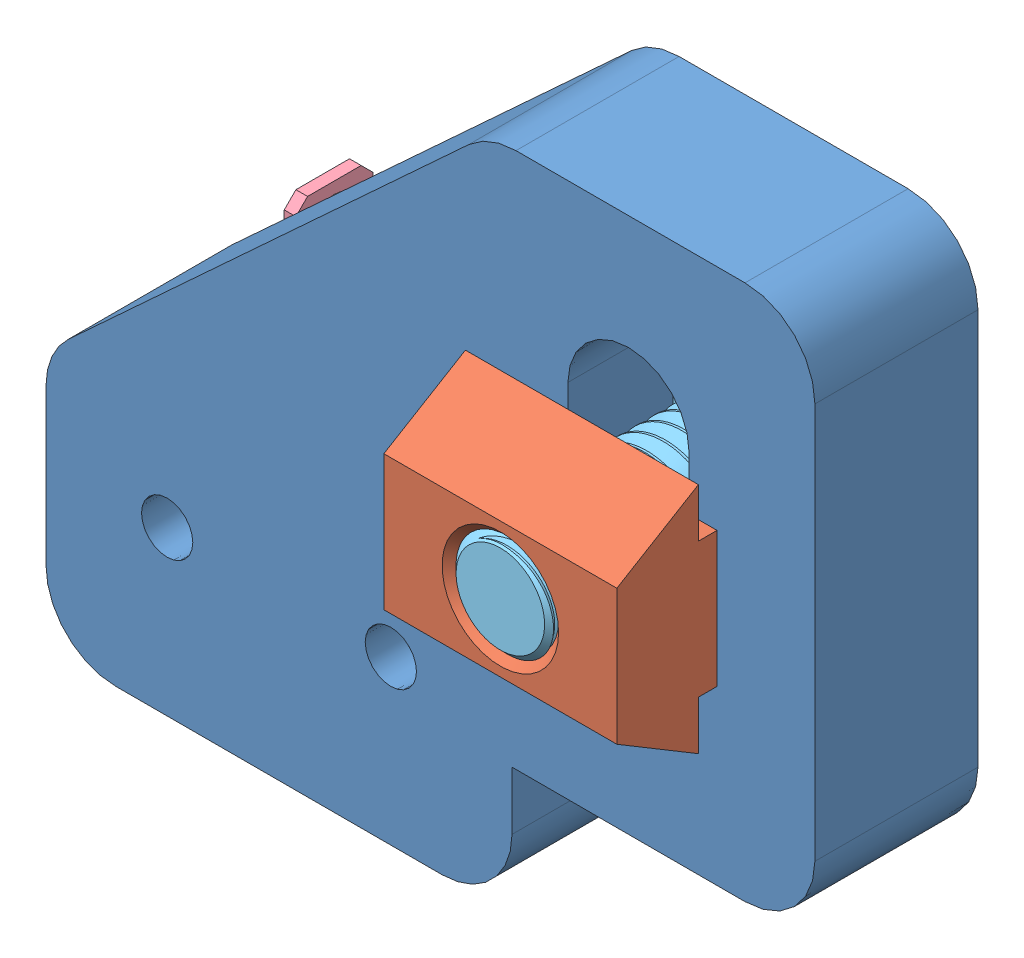
SolidWorks assembly Z Endstop, configuration Default. Lengths in mm.
Overall size (33 31.91 21.1).
6 component instances, 5 part files, 12 mates.
Components (placement in the parent):
- Z Endstop Mount V2-1: Z Endstop Mount V2 [Default] at origin size (33 28.5 7)
- HNTTSN5-5-1: HNTTSN5-5 [Default] at (25 17 8.2) x (0 0 -1) z (1 0 0) size (4.3 10 10)
- 3mmX12mm_Buttonhead(McMaster_92095A183)-1: 3mmX12mm_Buttonhead(McMaster_92095A183) [92095A183] at (14.8 7 -8.2) x (-0.955272 0.295729 0) z (0 0 -1) size (5.7 5.7 13.97)
- 3mmX12mm_Buttonhead(McMaster_92095A183)-2: 3mmX12mm_Buttonhead(McMaster_92095A183) [92095A183] at (5.3 7 -8.2) x (-0.949865 -0.312661 0) z (0 0 -1) size (5.7 5.7 13.97)
- Micro Switch Button-1: Micro Switch Button [Default] at (10.9 4.6 -3.175) x (0 0 -1) z (-1 0 0) size (6.75 16.71 19.86)
- 5mmX10mm_Buttonhead(McMaster_91239A224)-1: 5mmX10mm_Buttonhead(McMaster_91239A224) [91239A224] at (25 17 -0.25) x (0.923728 0.383049 0) z (0 0 -1) size (9.5 9.5 13.21)
Mates (geometry in assembly coordinates):
- Concentric4: concentric: point of Z Endstop Mount V2-1; cylinder of 5mmX10mm_Buttonhead(McMaster_91239A224)-1 through (25 17 -0.25) axis (0 0 -1) radius 4.75
- Coincident6: coincident anti-aligned: plane of Z Endstop Mount V2-1 through (25 21 2.5) normal (0 0 -1); plane of 5mmX10mm_Buttonhead(McMaster_91239A224)-1 through (23.1805 21.3877 2.5) normal (0 0 1)
- Coincident7: coincident anti-aligned: plane of Z Endstop Mount V2-1 through (30 8.5 0) normal (0 0 -1); plane of Micro Switch Button-1 through (19.7 9.2 0) normal (0 0 1)
- Concentric5: concentric aligned: cylinder of Z Endstop Mount V2-1 through (14.8 7 7) axis (0 0 -1) radius 1.1; cylinder of Micro Switch Button-1 through (14.8 7 0) axis (0 0 -1) radius 1.35
- Parallel2: parallel aligned: plane of Z Endstop Mount V2-1 through (3 0 7) normal (0 -1 0); plane of Micro Switch Button-1 through (0.85 0.05 -6.35) normal (0 -1 0)
- Concentric6: concentric aligned: cylinder of 3mmX12mm_Buttonhead(McMaster_92095A183)-1 through (14.8 7 -8.2) axis (0 0 -1) radius 2.85; cylinder of Micro Switch Button-1 through (14.8 7 0) axis (0 0 -1) radius 1.35
- Concentric7: concentric aligned: cylinder of 3mmX12mm_Buttonhead(McMaster_92095A183)-2 through (5.3 7 -8.2) axis (0 0 -1) radius 2.85; cylinder of Micro Switch Button-1 through (5.3 7 0) axis (0 0 -1) radius 1.35
- Coincident9: coincident anti-aligned: plane of 3mmX12mm_Buttonhead(McMaster_92095A183)-1 through (13.9572 4.2775 -6.55) normal (0 0 1); plane of Micro Switch Button-1 through (14.8 7 -6.55) normal (0 0 -1)
- Coincident10: coincident anti-aligned: plane of 3mmX12mm_Buttonhead(McMaster_92095A183)-2 through (6.1911 4.2929 -6.55) normal (0 0 1); plane of Micro Switch Button-1 through (5.3 7 -6.55) normal (0 0 -1)
- Concentric8: concentric anti-aligned: cylinder of HNTTSN5-5-1 through (25 17 8.2) axis (0 0 1) radius 2.067; cylinder of 5mmX10mm_Buttonhead(McMaster_91239A224)-1 through (25 17 -0.25) axis (0 0 -1) radius 4.75
- Distance1: distance = 2 mm anti-aligned: plane of HNTTSN5-5-1 through (30 12 9) normal (0 0 -1); plane of Z Endstop Mount V2-1 through (30 8.5 7) normal (0 0 1)
- Parallel3: parallel aligned: plane of Z Endstop Mount V2-1 through (20 3 7) normal (1 0 0); plane of HNTTSN5-5-1 through (30 17 8.2) normal (1 0 0)
